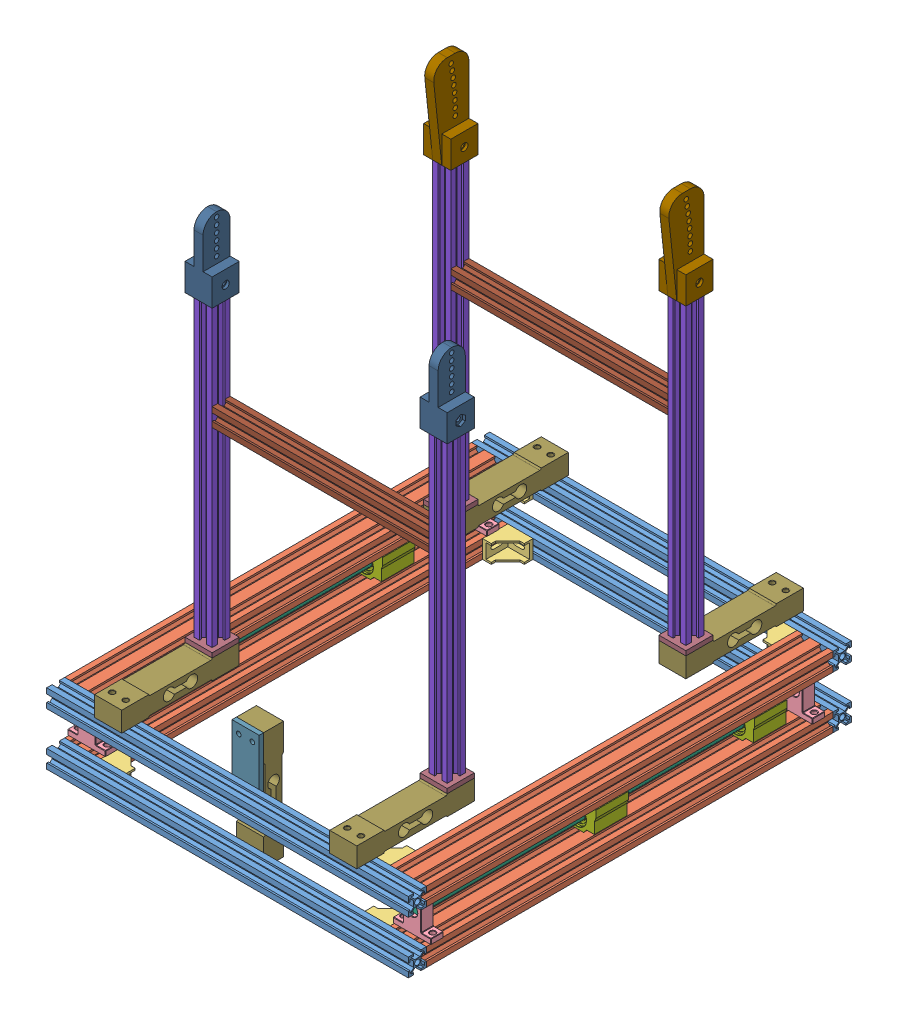
SolidWorks assembly Balança_Alt2, configuration Default. Lengths in mm.
Overall size (402 535 494).
56 component instances, 14 part files, 55 mates.
Components (placement in the parent):
- Quadrado2040-1: Quadrado2040 [Default] at (-124.633 620.1559 -302.6488) x (1 0 0) z (0 -1 0) size (400 490 20)
  - 20x20x400_profile-4: 20x20x400_profile [Default] at (-5.8923 594.8177 297.0396) x (0 1 0) z (0 0 1) size (20 400 20)
  - 20x20x400_profile-5: 20x20x400_profile [Default] at (-405.8923 124.8177 297.0396) x (0 -1 0) z (0 0 1) size (20 400 20)
  - 20x40x450_profile-3: 20x40x450_profile [Default] at (-395.8923 134.8177 297.0396) size (40 450 20)
  - 20x40x450_profile-4: 20x40x450_profile [Default] at (-35.8923 134.8177 297.0396) size (40 450 20)
  - cantoneira_20x20-1: cantoneira_20x20 [Default] at (-45.8923 134.8177 307.0396) x (0 0 -1) z (1 0 0) size (20 28 28)
  - cantoneira_20x20-2: cantoneira_20x20 [Default] at (-45.8923 584.8177 307.0396) x (0 0 -1) z (0 1 0) size (20 28 28)
  - cantoneira_20x20-3: cantoneira_20x20 [Default] at (-365.8923 584.8177 307.0396) x (0 0 -1) z (-1 0 0) size (20 28 28)
  - cantoneira_20x20-4: cantoneira_20x20 [Default] at (-365.8923 134.8177 307.0396) x (0 0 -1) z (0 -1 0) size (20 28 28)
- Quadrado2040-2: Quadrado2040 [Default] at (-124.633 678.1559 -302.6488) x (1 0 0) z (0 -1 0) size (400 490 20)
  - 20x20x400_profile-4: 20x20x400_profile [Default] at (-5.8923 594.8177 297.0396) x (0 1 0) z (0 0 1) size (20 400 20)
  - 20x20x400_profile-5: 20x20x400_profile [Default] at (-405.8923 124.8177 297.0396) x (0 -1 0) z (0 0 1) size (20 400 20)
  - 20x40x450_profile-3: 20x40x450_profile [Default] at (-395.8923 134.8177 297.0396) size (40 450 20)
  - 20x40x450_profile-4: 20x40x450_profile [Default] at (-35.8923 134.8177 297.0396) size (40 450 20)
  - cantoneira_20x20-1: cantoneira_20x20 [Default] at (-45.8923 134.8177 307.0396) x (0 0 -1) z (1 0 0) size (20 28 28)
  - cantoneira_20x20-2: cantoneira_20x20 [Default] at (-45.8923 584.8177 307.0396) x (0 0 -1) z (0 1 0) size (20 28 28)
  - cantoneira_20x20-3: cantoneira_20x20 [Default] at (-365.8923 584.8177 307.0396) x (0 0 -1) z (-1 0 0) size (20 28 28)
  - cantoneira_20x20-4: cantoneira_20x20 [Default] at (-365.8923 134.8177 307.0396) x (0 0 -1) z (0 -1 0) size (20 28 28)
- SK12-5: SK12 [Valor predeterminado] at (-504.83 350.1 -192.831) size (42 37.6 14)
  - Shaft support SK12-1: Shaft support SK12 [Valor predeterminado] at (-5.6953 6.0163 42) size (42 37.5 14)
  - m4x16-2: m4x16 [Valor predeterminado] at (4.3047 16.0441 42) x (-1 0 0) z (0 0.924225 0.381849) size (20 7 7)
- SK12-9: SK12 [Valor predeterminado] at (-504.83 350.1 229.169) size (42 37.6 14)
  - Shaft support SK12-1: Shaft support SK12 [Valor predeterminado] at (-5.6953 6.0163 42) size (42 37.5 14)
  - m4x16-2: m4x16 [Valor predeterminado] at (4.3047 16.0441 42) x (-1 0 0) z (0 0.924225 0.381849) size (20 7 7)
- SK12-10: SK12 [Valor predeterminado] at (-156.2206 350.1 -108.831) x (-1 0 0) z (0 0 -1) size (42 37.6 14)
  - Shaft support SK12-1: Shaft support SK12 [Valor predeterminado] at (-5.6953 6.0163 42) size (42 37.5 14)
  - m4x16-2: m4x16 [Valor predeterminado] at (4.3047 16.0441 42) x (-1 0 0) z (0 0.924225 0.381849) size (20 7 7)
- SK12-11: SK12 [Valor predeterminado] at (-156.2206 350.1 313.169) x (-1 0 0) z (0 0 -1) size (42 37.6 14)
  - Shaft support SK12-1: Shaft support SK12 [Valor predeterminado] at (-5.6953 6.0163 42) size (42 37.5 14)
  - m4x16-2: m4x16 [Valor predeterminado] at (4.3047 16.0441 42) x (-1 0 0) z (0 0.924225 0.381849) size (20 7 7)
- EixoLinear12mm-1: EixoLinear12mm [Default] at (-510.5253 356.1163 71.6299) x (0.524668 0.851307 0) z (0 0 1) size (12 12 400)
- EixoLinear12mm-2: EixoLinear12mm [Default] at (-150.5253 356.1163 73.8717) x (0.495907 0.868376 0) z (0 0 1) size (12 12 400)
- SC12UU-1: SC12UU [Default] at (-510.5253 371.1163 174.0893) size (42 28 36)
- SC12UU-2: SC12UU [Default] at (-150.5253 371.1163 77.8174) size (42 28 36)
- SC12UU-3: SC12UU [Default] at (-150.5253 371.1163 -97.9122) size (42 28 36)
- SC12UU-4: SC12UU [Default] at (-510.5253 371.1163 -46.4835) size (42 28 36)
- 20x20x500_profile-1: 20x20x500_profile [Default] at (-460.5253 418.1163 -74.831) size (20 350 20)
- 20x20x500_profile-2: 20x20x500_profile [Default] at (-200.5253 418.1163 -74.831) x (-1 0 0) z (0 0 -1) size (20 350 20)
- EncaixeAsaDianteiro-1: EncaixeAsaDianteiro [Default] at (-460.5253 748.1163 -74.831) x (-1 0 0) z (0 0 -1) size (30 100 38.89)
- EncaixeAsaTraseiro-1: EncaixeAsaTraseiro [Default] at (-460.5253 748.1163 189.169) x (-1 0 0) z (0 0 -1) size (30 80 30)
- EncaixeAsaDianteiro-4: EncaixeAsaDianteiro [Default] at (-200.5253 748.1163 -74.831) x (-1 0 0) z (0 0 -1) size (30 100 38.89)
- 20x20x200_profile-3: 20x20x200_profile [Default] at (-210.5253 638.8952 -74.831) x (0 1 0) z (0 0 1) size (20 240 20)
- load_cell_big_20kg-1: load_cell_big_20kg [Default] at (-345.5253 378.1163 266.169) x (1 0 0) z (0 -1 0) size (30 22 130)
- load_cell_big_20kg-2: load_cell_big_20kg [Default] at (-475.5253 402.1163 -124.831) size (30 22 130)
- Placa_de_conexao_celula_de_carga-1: Placa_de_conexao_celula_de_carga [Default] at (-460.5253 413.1163 -74.831) size (30 5 30)
- load_cell_big_20kg-4: load_cell_big_20kg [Default] at (-185.5253 402.1163 -124.831) x (-1 0 0) z (0 0 -1) size (30 22 130)
- Placa_de_conexao_celula_de_carga-2: Placa_de_conexao_celula_de_carga [Default] at (-200.5253 413.1163 -74.831) x (-1 0 0) z (0 0 -1) size (30 5 30)
- load_cell_big_20kg-7: load_cell_big_20kg [Default] at (-475.5253 402.1163 239.169) size (30 22 130)
- Placa_de_conexao_celula_de_carga-5: Placa_de_conexao_celula_de_carga [Default] at (-460.5253 413.1163 189.169) size (30 5 30)
- 20x20x500_profile-5: 20x20x500_profile [Default] at (-460.5253 418.1163 189.169) size (20 350 20)
- load_cell_big_20kg-8: load_cell_big_20kg [Default] at (-185.5253 402.1163 239.169) x (-1 0 0) z (0 0 -1) size (30 22 130)
- Placa_de_conexao_celula_de_carga-6: Placa_de_conexao_celula_de_carga [Default] at (-200.5253 413.1163 189.169) x (-1 0 0) z (0 0 -1) size (30 5 30)
- 20x20x500_profile-6: 20x20x500_profile [Default] at (-200.5253 418.1163 189.169) x (-1 0 0) z (0 0 -1) size (20 350 20)
- EncaixeAsaTraseiro-5: EncaixeAsaTraseiro [Default] at (-200.5253 748.1163 189.169) size (30 80 30)
- 20x20x200_profile-5: 20x20x200_profile [Default] at (-210.5253 638.8952 189.169) x (0 1 0) z (0 0 1) size (20 240 20)
- Placa_de_conexao_celula_de_carga_2-1: Placa_de_conexao_celula_de_carga_2 [Default] at (-330.5253 407.1163 277.169) x (0 1 0) z (1 0 0) size (72 5 30)
Mates (geometry in assembly coordinates):
- Coincident5: coincident anti-aligned: plane of Quadrado2040-1/20x40x450_profile-3 through (-516.5253 333.1163 282.169) normal (0 1 0); plane of SK12-5/Shaft support SK12-1 through (-510.5253 333.1163 -157.831) normal (0 -1 0)
- Distance1: distance = 1 mm aligned: plane of SK12-5/Shaft support SK12-1 through (-531.5253 307.9299 -157.831) normal (-1 0 0); plane of Quadrado2040-1/20x40x450_profile-3 through (-530.5253 319.1163 282.169) normal (-1 0 0)
- Distance2: distance = 10 mm aligned: plane of SK12-5/Shaft support SK12-1 through (-510.5253 307.9299 -157.831) normal (0 0 -1); plane of Quadrado2040-1/20x40x450_profile-3 through (-520.5253 323.1163 -167.831) normal (0 0 -1)
- Concentric1: concentric anti-aligned: cylinder of SK12-9/Shaft support SK12-1 through (-510.5253 356.1163 264.169) axis (0 0 1) radius 6; cylinder of EixoLinear12mm-1 through (-510.5253 356.1163 271.6299) axis (0 0 -1) radius 6
- Concentric2: concentric aligned: cylinder of SK12-10/Shaft support SK12-1 through (-150.5253 356.1163 -143.831) axis (0 0 -1) radius 6; cylinder of EixoLinear12mm-2 through (-150.5253 356.1163 273.8717) axis (0 0 -1) radius 6
- Concentric3: concentric anti-aligned: cylinder of EixoLinear12mm-1 through (-510.5253 356.1163 271.6299) axis (0 0 -1) radius 6; cylinder of SC12UU-1 through (-510.5253 356.1163 204.3646) axis (0 0 1) radius 6
- Concentric4: concentric anti-aligned: cylinder of EixoLinear12mm-1 through (-510.5253 356.1163 271.6299) axis (0 0 -1) radius 6; cylinder of SC12UU-4 through (-510.5253 356.1163 -16.2082) axis (0 0 1) radius 6
- Coincident9: coincident anti-aligned: cylinder of EixoLinear12mm-2 through (-150.5253 356.1163 273.8717) axis (0 0 -1) radius 6; circle of SC12UU-3
- Coincident10: coincident anti-aligned: cylinder of EixoLinear12mm-2 through (-150.5253 356.1163 273.8717) axis (0 0 -1) radius 6; circle of SC12UU-2
- Coincident11: coincident anti-aligned: plane of SC12UU-1 through (-499.5253 371.1163 192.0893) normal (0 1 0); plane of Quadrado2040-2/20x40x450_profile-3 through (-490.5253 371.1163 282.169) normal (0 -1 0)
- Coincident12: coincident anti-aligned: plane of SC12UU-4 through (-521.5253 371.1163 -28.4835) normal (0 1 0); plane of Quadrado2040-2/20x40x450_profile-3 through (-490.5253 371.1163 282.169) normal (0 -1 0)
- Coincident13: coincident anti-aligned: plane of SC12UU-2 through (-139.5253 371.1163 95.8174) normal (0 1 0); plane of Quadrado2040-2/20x40x450_profile-4 through (-156.5253 371.1163 282.169) normal (0 -1 0)
- Coincident14: coincident anti-aligned: plane of SC12UU-3 through (-161.5253 371.1163 -79.9122) normal (0 1 0); plane of Quadrado2040-2/20x40x450_profile-4 through (-156.5253 371.1163 282.169) normal (0 -1 0)
- Coincident15: coincident aligned: plane of Quadrado2040-1/20x20x400_profile-4 through (-530.5253 319.1163 302.169) normal (0 0 1); plane of Quadrado2040-2/20x20x400_profile-4 through (-530.5253 377.1163 302.169) normal (0 0 1)
- Coincident16: coincident aligned: plane of Quadrado2040-1/20x40x450_profile-3 through (-530.5253 333.1163 282.169) normal (-1 0 0); plane of Quadrado2040-2/20x40x450_profile-3 through (-530.5253 391.1163 282.169) normal (-1 0 0)
- Coincident25: coincident anti-aligned: plane of 20x20x500_profile-1 through (-460.5253 768.1163 -74.831) normal (0 1 0); plane of EncaixeAsaDianteiro-1 through (-460.5253 768.1163 -74.831) normal (0 -1 0)
- Coincident38: coincident anti-aligned: plane of 20x20x500_profile-2 through (-200.5253 768.1163 -74.831) normal (0 1 0); plane of EncaixeAsaDianteiro-4 through (-200.5253 768.1163 -74.831) normal (0 -1 0)
- Coincident63: coincident anti-aligned: plane of 20x20x500_profile-1 through (-450.5253 768.1163 -84.831) normal (1 0 0); plane of 20x20x200_profile-3 through (-450.5253 638.8952 -74.831) normal (-1 0 0)
- Coincident64: coincident aligned: plane of 20x20x500_profile-1 through (-456.5253 768.1163 -84.831) normal (0 0 -1); plane of 20x20x200_profile-3 through (-450.5253 642.8952 -84.831) normal (0 0 -1)
- Coincident65: coincident anti-aligned: plane of 20x20x500_profile-2 through (-210.5253 768.1163 -78.831) normal (-1 0 0); plane of 20x20x200_profile-3 through (-210.5253 638.8952 -74.831) normal (1 0 0)
- Coincident66: coincident anti-aligned: plane of 20x20x500_profile-1 through (-456.5253 768.1163 -84.831) normal (0 0 -1); plane of EncaixeAsaDianteiro-1 through (-450.5253 768.1163 -84.831) normal (0 0 1)
- Coincident67: coincident anti-aligned: plane of 20x20x500_profile-1 through (-450.5253 768.1163 -84.831) normal (1 0 0); plane of EncaixeAsaDianteiro-1 through (-450.5253 768.1163 -64.831) normal (-1 0 0)
- Coincident68: coincident anti-aligned: plane of 20x20x500_profile-2 through (-204.5253 768.1163 -84.831) normal (0 0 -1); plane of EncaixeAsaDianteiro-4 through (-190.5253 768.1163 -84.831) normal (0 0 1)
- Coincident69: coincident anti-aligned: plane of 20x20x500_profile-2 through (-210.5253 768.1163 -64.831) normal (-1 0 0); plane of EncaixeAsaDianteiro-4 through (-210.5253 768.1163 -64.831) normal (1 0 0)
- Coincident80: coincident anti-aligned: plane of Quadrado2040-2/20x20x400_profile-5 through (-130.5253 391.1163 -181.831) normal (0 1 0); plane of load_cell_big_20kg-2 through (-445.5253 391.1163 -124.831) normal (0 -1 0)
- Width1: width anti-aligned: plane of load_cell_big_20kg-2 through (-475.5253 402.1163 -124.831) normal (-1 0 0); plane of load_cell_big_20kg-2 through (-445.5253 402.1163 -124.831) normal (1 0 0); plane of 20x20x500_profile-1 through (-450.5253 768.1163 -70.831) normal (1 0 0); plane of 20x20x500_profile-1 through (-470.5253 768.1163 -70.831) normal (-1 0 0)
- Coincident85: coincident anti-aligned: plane of load_cell_big_20kg-2 through (-445.5253 413.1163 -124.831) normal (0 1 0); plane of Placa_de_conexao_celula_de_carga-1 through (-460.5253 413.1163 -74.831) normal (0 -1 0)
- Coincident86: coincident aligned: plane of load_cell_big_20kg-2 through (-445.5253 402.1163 -59.831) normal (0 0 1); plane of Placa_de_conexao_celula_de_carga-1 through (-475.5253 418.1163 -59.831) normal (0 0 1)
- Coincident87: coincident aligned: plane of load_cell_big_20kg-2 through (-475.5253 402.1163 -124.831) normal (-1 0 0); plane of Placa_de_conexao_celula_de_carga-1 through (-475.5253 418.1163 -89.831) normal (-1 0 0)
- Parallel2: parallel aligned: plane of 20x20x500_profile-1 through (-470.5253 768.1163 -84.831) normal (-1 0 0); plane of Placa_de_conexao_celula_de_carga-1 through (-475.5253 418.1163 -89.831) normal (-1 0 0)
- Width2: width anti-aligned: plane of Placa_de_conexao_celula_de_carga-1 through (-475.5253 418.1163 -89.831) normal (-1 0 0); plane of Placa_de_conexao_celula_de_carga-1 through (-445.5253 418.1163 -89.831) normal (1 0 0); plane of 20x20x500_profile-1 through (-450.5253 768.1163 -84.831) normal (1 0 0); plane of 20x20x500_profile-1 through (-470.5253 768.1163 -84.831) normal (-1 0 0)
- Width3: width anti-aligned: plane of Placa_de_conexao_celula_de_carga-1 through (-475.5253 418.1163 -89.831) normal (0 0 -1); plane of Placa_de_conexao_celula_de_carga-1 through (-475.5253 418.1163 -59.831) normal (0 0 1); plane of 20x20x500_profile-1 through (-470.5253 768.1163 -64.831) normal (0 0 1); plane of 20x20x500_profile-1 through (-470.5253 768.1163 -84.831) normal (0 0 -1)
- Coincident90: coincident anti-aligned: plane of 20x20x500_profile-1 through (-460.5253 418.1163 -74.831) normal (0 -1 0); plane of Placa_de_conexao_celula_de_carga-1 through (-460.5253 418.1163 -74.831) normal (0 1 0)
- Distance5: distance = 2 mm aligned: plane of load_cell_big_20kg-2 through (-445.5253 402.1163 -189.831) normal (0 0 -1); plane of Quadrado2040-2/20x20x400_profile-5 through (-130.5253 391.1163 -187.831) normal (0 0 -1)
- Distance6: distance = 2 mm aligned: plane of load_cell_big_20kg-7 through (-445.5253 402.1163 304.169) normal (0 0 1); plane of Quadrado2040-2/20x20x400_profile-4 through (-530.5253 391.1163 302.169) normal (0 0 1)
- Coincident101: coincident anti-aligned: plane of Quadrado2040-2/20x20x400_profile-4 through (-530.5253 391.1163 296.169) normal (0 1 0); plane of load_cell_big_20kg-7 through (-445.5253 391.1163 239.169) normal (0 -1 0)
- Coincident102: coincident aligned: plane of load_cell_big_20kg-2 through (-475.5253 402.1163 -124.831) normal (-1 0 0); plane of load_cell_big_20kg-7 through (-475.5253 402.1163 239.169) normal (-1 0 0)
- Coincident103: coincident aligned: plane of load_cell_big_20kg-7 through (-475.5253 402.1163 239.169) normal (-1 0 0); plane of Placa_de_conexao_celula_de_carga-5 through (-475.5253 418.1163 174.169) normal (-1 0 0)
- Coincident104: coincident aligned: plane of load_cell_big_20kg-7 through (-445.5253 402.1163 174.169) normal (0 0 -1); plane of Placa_de_conexao_celula_de_carga-5 through (-475.5253 418.1163 174.169) normal (0 0 -1)
- Coincident105: coincident anti-aligned: plane of load_cell_big_20kg-7 through (-445.5253 413.1163 239.169) normal (0 1 0); plane of Placa_de_conexao_celula_de_carga-5 through (-460.5253 413.1163 189.169) normal (0 -1 0)
- Coincident106: coincident anti-aligned: plane of Placa_de_conexao_celula_de_carga-5 through (-460.5253 418.1163 189.169) normal (0 1 0); plane of 20x20x500_profile-5 through (-460.5253 418.1163 189.169) normal (0 -1 0)
- Width4: width anti-aligned: plane of Placa_de_conexao_celula_de_carga-5 through (-445.5253 418.1163 174.169) normal (1 0 0); plane of Placa_de_conexao_celula_de_carga-5 through (-475.5253 418.1163 174.169) normal (-1 0 0); plane of 20x20x500_profile-5 through (-470.5253 768.1163 193.169) normal (-1 0 0); plane of 20x20x500_profile-5 through (-450.5253 768.1163 193.169) normal (1 0 0)
- Width5: width anti-aligned: plane of 20x20x500_profile-5 through (-470.5253 768.1163 199.169) normal (0 0 1); plane of 20x20x500_profile-5 through (-470.5253 768.1163 179.169) normal (0 0 -1); plane of Placa_de_conexao_celula_de_carga-5 through (-475.5253 418.1163 174.169) normal (0 0 -1); plane of Placa_de_conexao_celula_de_carga-5 through (-475.5253 418.1163 204.169) normal (0 0 1)
- Coincident107: coincident anti-aligned: plane of EncaixeAsaTraseiro-1 through (-460.5253 768.1163 189.169) normal (0 -1 0); plane of 20x20x500_profile-5 through (-460.5253 768.1163 189.169) normal (0 1 0)
- Coincident108: coincident anti-aligned: plane of EncaixeAsaTraseiro-1 through (-450.5253 768.1163 199.169) normal (-1 0 0); plane of 20x20x500_profile-5 through (-450.5253 768.1163 193.169) normal (1 0 0)
- Coincident109: coincident anti-aligned: plane of EncaixeAsaTraseiro-1 through (-450.5253 768.1163 179.169) normal (0 0 1); plane of 20x20x500_profile-5 through (-456.5253 768.1163 179.169) normal (0 0 -1)
- Coincident110: coincident anti-aligned: plane of 20x20x500_profile-5 through (-450.5253 768.1163 193.169) normal (1 0 0); plane of 20x20x200_profile-5 through (-450.5253 638.8952 189.169) normal (-1 0 0)
- Coincident111: coincident aligned: plane of 20x20x500_profile-5 through (-456.5253 768.1163 199.169) normal (0 0 1); plane of 20x20x200_profile-5 through (-450.5253 642.8952 199.169) normal (0 0 1)
- Coincident112: coincident aligned: plane of 20x20x200_profile-3 through (-450.5253 648.8952 -84.831) normal (0 1 0); plane of 20x20x200_profile-5 through (-450.5253 648.8952 179.169) normal (0 1 0)
- Width6: width anti-aligned: plane of load_cell_big_20kg-1 through (-345.5253 378.1163 266.169) normal (-1 0 0); plane of load_cell_big_20kg-1 through (-315.5253 378.1163 266.169) normal (1 0 0); plane of Quadrado2040-2/20x20x400_profile-4 through (-130.5253 381.1163 292.169) normal (1 0 0); plane of Quadrado2040-2/20x20x400_profile-4 through (-530.5253 381.1163 292.169) normal (-1 0 0)
- Coincident113: coincident aligned: plane of Quadrado2040-1/20x20x400_profile-4 through (-530.5253 313.1163 282.169) normal (0 -1 0); plane of load_cell_big_20kg-1 through (-315.5253 313.1163 266.169) normal (0 -1 0)
- Coincident114: coincident aligned: plane of load_cell_big_20kg-1 through (-315.5253 443.1163 266.169) normal (0 1 0); plane of Placa_de_conexao_celula_de_carga_2-1 through (-345.5253 443.1163 282.169) normal (0 1 0)
- Coincident115: coincident aligned: plane of load_cell_big_20kg-1 through (-345.5253 378.1163 266.169) normal (-1 0 0); plane of Placa_de_conexao_celula_de_carga_2-1 through (-345.5253 371.1163 282.169) normal (-1 0 0)
- Coincident116: coincident anti-aligned: plane of load_cell_big_20kg-1 through (-315.5253 378.1163 277.169) normal (0 0 1); plane of Placa_de_conexao_celula_de_carga_2-1 through (-330.5253 407.1163 277.169) normal (0 0 -1)
- Coincident117: coincident anti-aligned: plane of Quadrado2040-2/20x20x400_profile-4 through (-530.5253 391.1163 282.169) normal (0 0 -1); plane of Placa_de_conexao_celula_de_carga_2-1 through (-330.5253 407.1163 282.169) normal (0 0 1)
